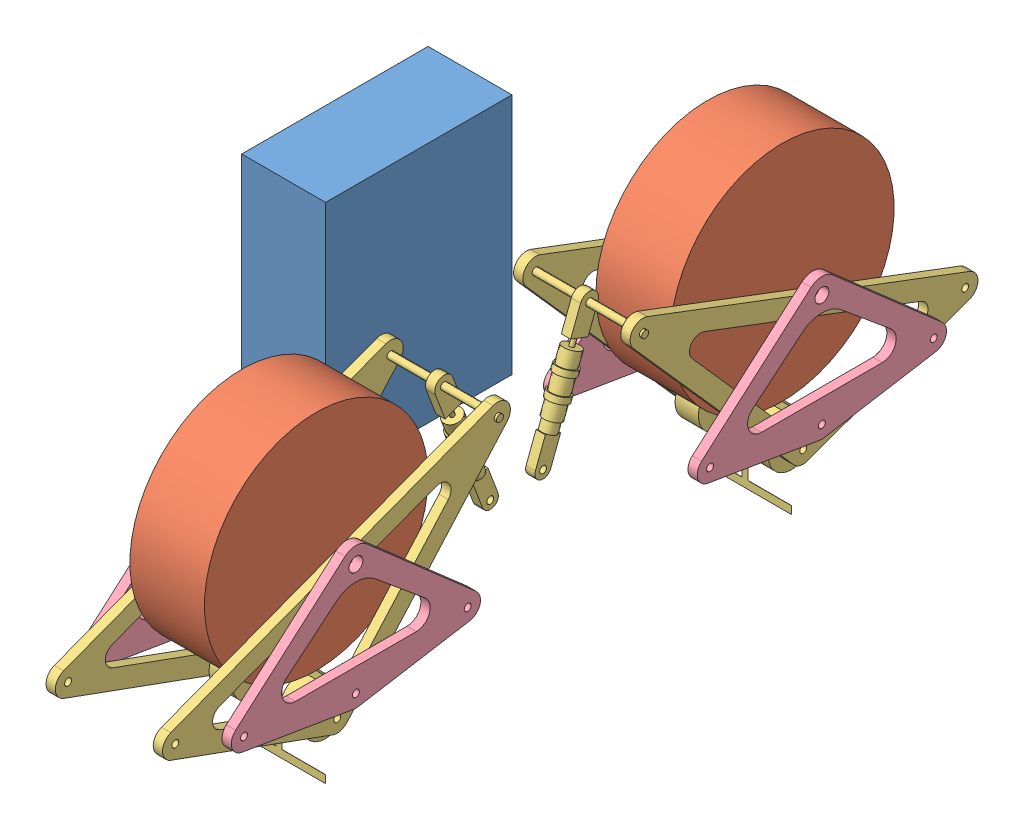
SolidWorks assembly drive_assembly, configuration Default. Lengths in mm.
Overall size (346.08 495.3 1111.25).
9 component instances, 4 part files, 9 mates.
Components (placement in the parent):
- motor-1: motor [Default] at (4.9823 194.7584 300.6208) size (114.3 330.2 254)
- drive_wheel-1: drive_wheel [Default] at (189.1323 143.9584 -16.8792) x (0 0 -1) z (1 0 0) size (304.8 304.8 101.6)
- vertical_stability-1: vertical_stability [Default] at (189.1323 -124.9768 -16.8792) size (165.1 348.85 530.75)
- drive_wheel-2: drive_wheel [Default] at (189.1323 143.9584 618.1208) x (0 0 1) z (-1 0 0) size (304.8 304.8 101.6)
- vertical_stability-2: vertical_stability [Default] at (189.1323 -124.9768 618.1208) x (-1 0 0) z (0 0 -1) size (165.1 348.85 530.75)
- Part1^drive_assembly-1: Part1^drive_assembly [Default] at (84.3573 143.9584 -16.8792) size (12.7 192.09 339.73) (virtual)
- Part1^drive_assembly-2: Part1^drive_assembly [Default] at (281.2073 143.9584 -16.8792) size (12.7 192.09 339.73) (virtual)
- Part1^drive_assembly-3: Part1^drive_assembly [Default] at (84.3573 143.9584 618.1208) size (12.7 192.09 339.73) (virtual)
- Part1^drive_assembly-4: Part1^drive_assembly [Default] at (281.2073 143.9584 618.1208) size (12.7 192.09 339.73) (virtual)
Mates (geometry in assembly coordinates):
- Belt Width: distance = 76.2 mm anti-aligned: plane of drive_wheel-1 through (138.3323 143.9584 -16.8792) normal (-1 0 0); plane of motor-1 through (62.1323 194.7584 300.6208) normal (1 0 0)
- Drive Wheel Axis: concentric aligned: circle of drive_wheel-1; circle of vertical_stability-1
- Center Drive Wheel on Stabilizer: coincident aligned: plane of drive_wheel-1 through (189.1323 143.9584 -16.8792) normal (1 0 0); plane of vertical_stability-1 through (189.1323 -124.9768 -16.8792) normal (1 0 0)
- Fix Motor Bottom to Bottom of Sled: coincident: plane of motor-1 through (62.1323 29.6584 427.6208) normal (0 -1 0); point of vertical_stability-1
- Distance Between Wheels: distance = 317.5 mm anti-aligned: plane of drive_wheel-1 through (189.1323 143.9584 -16.8792) normal (0 0 -1); plane of motor-1 through (4.9823 194.7584 300.6208) normal (0 0 1)
- Straight I-Beam: parallel aligned: plane of motor-1 through (4.9823 194.7584 300.6208) normal (0 0 1); plane of vertical_stability-1 through (189.1323 -124.9768 -16.7522) normal (0 0 1)
- Concentric1: concentric aligned: cylinder of drive_wheel-1 through (239.9323 143.9584 -16.8792) axis (-1 0 0) radius 152.4; cylinder of Part1^drive_assembly-1 through (97.0573 143.9584 -16.8792) axis (-1 0 0) radius 9.525
- Distance1: distance = 12.7 mm anti-aligned: plane of vertical_stability-1 through (109.7573 195.9412 201.6851) normal (-1 0 0); plane of Part1^drive_assembly-1 through (97.0573 143.9584 -16.8792) normal (1 0 0)
- Parallel2: parallel aligned: plane of Part1^drive_assembly-1 through (97.0573 23.3084 -16.8792) normal (0 1 0); plane of assembly through (0 0 0) normal (0 1 0)
